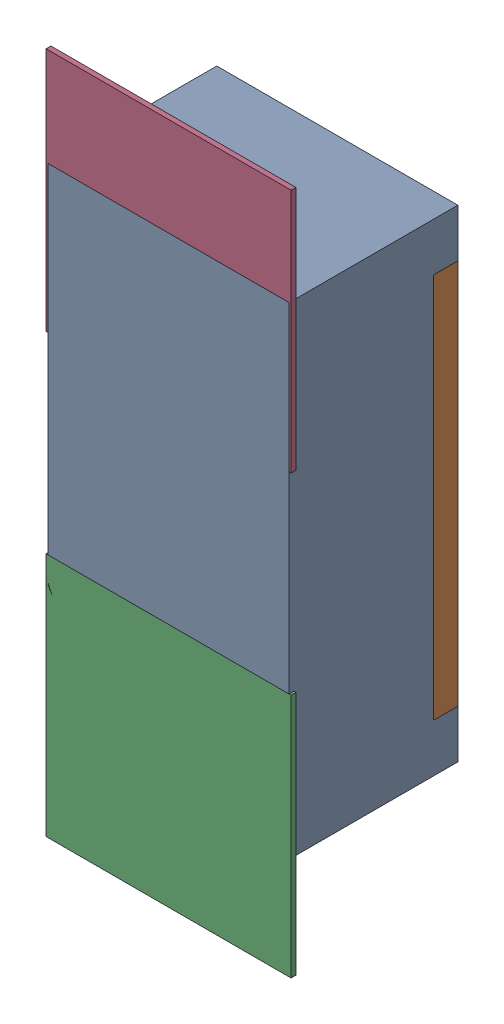
SolidWorks assembly R39, configuration Défaut. Lengths in mm.
Overall size (0.51 1.42 0.35).
5 component instances, 2 part files, 0 mates.
Components (placement in the parent):
- R0402-1: R0402 [Défaut] at (12.7761 -21.3288 -2.0818) x (0 1 0) z (0 0 -1) size (1 0.5 0.35)
- 6504207776-1: 6504207776 [Défaut] at (12.7762 -21.7859 -2.0918) size (0.51 0.51 0.01)
  - Extruded-1: Extruded [Défaut] at origin size (0.51 0.51 0.01)
- 6504207776-2: 6504207776 [Défaut] at (12.7762 -20.8788 -2.0918) size (0.51 0.51 0.01)
  - Extruded-1: Extruded [Défaut] at origin size (0.51 0.51 0.01)
